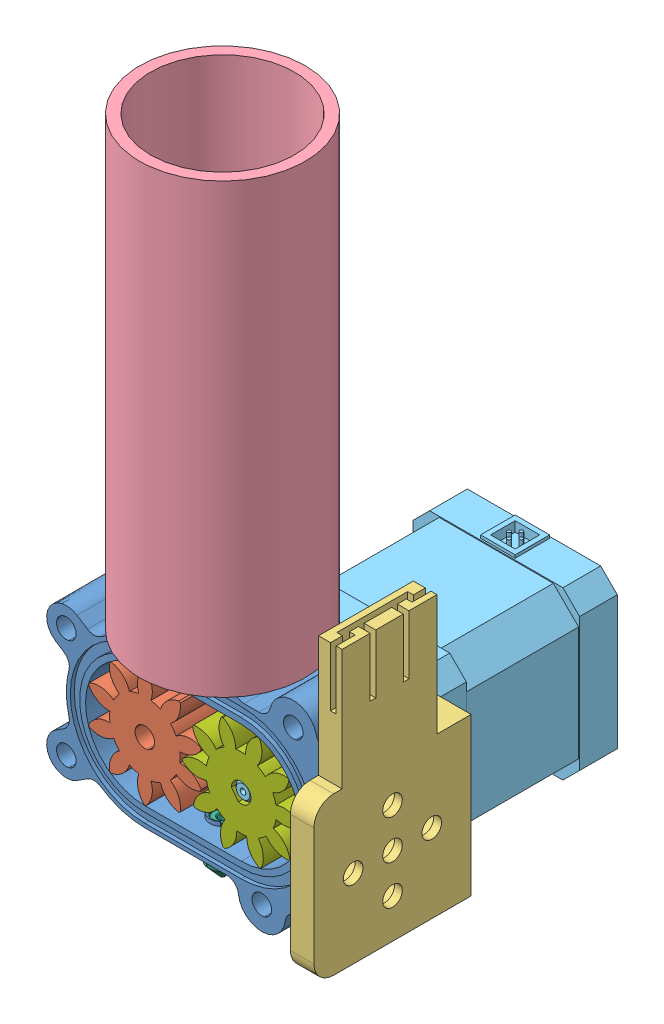
SolidWorks assembly NewGearPumpAssembly, configuration Default. Lengths in mm.
Overall size (81.5 167.89 88.12).
7 component instances, 7 part files, 15 mates.
Components (placement in the parent):
- body_newgearpump-1: body_newgearpump [Default] at (24.2488 34.5352 42.8873) size (74.75 55 22)
- Gear_newgearpump-2: Gear_newgearpump [Default] at (11.9988 34.5352 49.8873) x (-0.587539 -0.809196 0) z (0 0 1) size (30 28.68 15)
- Extruder_mount-1: Extruder_mount [Default] at (68.4988 34.5352 58.3873) x (0 0 -1) z (1 0 0) size (40 78.75 81.5)
- vat_newgearpump-1: vat_newgearpump [Default] at (24.2488 60.5352 57.3873) size (42.16 123.95 42.16)
- DC_Steppers-1: DC_Steppers [6627T91] at (36.4988 34.5352 27.4003) size (42.4 43.16 74.07)
- 3695N115_3D Printer Nozzle-1: 3695N115_3D Printer Nozzle [3695N115] at (24.2488 14.4352 57.3873) size (7 13.3 8.64)
- Gear_key_newgearpump-1: Gear_key_newgearpump [Default] at (36.4988 34.5352 49.8873) x (-0.800243 -0.599676 0) z (0 0 1) size (30 28.68 15)
Mates (geometry in assembly coordinates):
- Concentric1: concentric aligned: circle of body_newgearpump-1; circle of Gear_newgearpump-1
- Coincident1: coincident anti-aligned: plane of body_newgearpump-1 through (36.4988 34.5352 49.8873) normal (0 0 1); plane of Gear_newgearpump-1 through (36.4988 34.5352 44.8873) normal (0 0 -1)
- Concentric2: concentric aligned: circle of body_newgearpump-1; circle of Gear_newgearpump-2
- Coincident2: coincident anti-aligned: plane of body_newgearpump-1 through (36.4988 34.5352 49.8873) normal (0 0 1); plane of Gear_newgearpump-2 through (11.9988 34.5352 49.8873) normal (0 0 -1)
- Coincident3: coincident anti-aligned: plane of Extruder_mount-1 through (62.4988 54.5352 38.3873) normal (0 0 -1); plane of DC_Steppers-1 through (36.4988 34.5352 38.3873) normal (0 0 1)
- Concentric3: concentric anti-aligned: cylinder of Extruder_mount-1 through (51.9988 50.0352 38.3863) axis (0 0 1) radius 1.5; circle of DC_Steppers-1
- Concentric4: concentric anti-aligned: cylinder of Extruder_mount-1 through (20.9988 19.0352 38.3863) axis (0 0 1) radius 1.5; circle of DC_Steppers-1
- Concentric5: concentric anti-aligned: cylinder of body_newgearpump-1 through (36.4988 34.5352 42.8873) axis (0 0 1) radius 2.5; cylinder of DC_Steppers-1 through (36.4988 34.5352 64.4193) axis (0 0 -1) radius 2.25
- Concentric6: concentric anti-aligned: cylinder of vat_newgearpump-1 through (24.2488 174.3272 57.3873) axis (0 -1 0) radius 4.445; circle of body_newgearpump-1
- Coincident4: coincident anti-aligned: plane of vat_newgearpump-1 through (24.2488 60.5352 57.3873) normal (0 -1 0); plane of body_newgearpump-1 through (24.2488 60.5352 42.8873) normal (0 1 0)
- Coincident7: coincident anti-aligned: plane of body_newgearpump-1 through (41.7488 12.5352 42.8873) normal (0 0 -1); plane of Extruder_mount-1 through (10.4988 54.5352 42.8873) normal (0 0 1)
- Coincident5: coincident aligned: plane of body_newgearpump-1 through (11.9988 19.4352 49.8873) normal (0 1 0); plane of 3695N115_3D Printer Nozzle-1 through (24.2488 19.4352 57.3873) normal (0 1 0)
- Concentric7: concentric anti-aligned: circle of body_newgearpump-1; cylinder of 3695N115_3D Printer Nozzle-1 through (24.2488 19.4352 57.3873) axis (0 1 0) radius 0.4
- Concentric8: concentric anti-aligned: cylinder of DC_Steppers-1 through (36.4988 34.5352 64.4193) axis (0 0 -1) radius 2.25; cylinder of Gear_key_newgearpump-1 through (36.4988 34.5352 49.8873) axis (0 0 1) radius 2.49
- Coincident6: coincident anti-aligned: plane of body_newgearpump-1 through (36.4988 34.5352 49.8873) normal (0 0 1); plane of Gear_key_newgearpump-1 through (36.4988 34.5352 49.8873) normal (0 0 -1)
